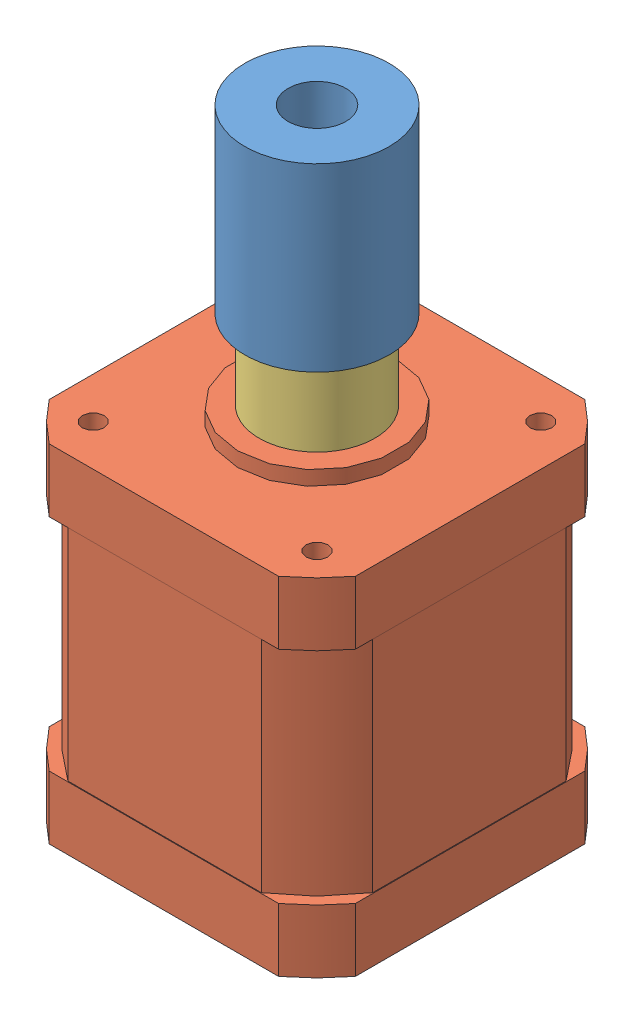
SolidWorks assembly z_motor_thrust_coupling_assembly, configuration Default. Lengths in mm.
Overall size (42.42 86 42.42).
4 component instances, 4 part files, 0 mates.
Components (placement in the parent):
- plumb_coupling_8mm_to_5mm-1: plumb_coupling_8mm_to_5mm [Default] at (304.071 41.773 434.2083) x (0.979819 0 -0.199886) z (0.199886 0 0.979819) size (20 25 20)
- 17HM19-2004S-1: 17HM19-2004S [Default] at (304.071 28.773 434.2083) x (0 0 -1) z (0 1 0) size (42.42 42.42 72)
- z_thrust_bearing_spacer_Z Thrust Bearing Spacer-1: z_thrust_bearing_spacer_Z Thrust Bearing Spacer [Default] at (304.071 30.773 434.2083) x (0.992689 0 -0.120701) z (0.120701 0 0.992689) size (16 10.8 16)
- m5_shim_0.2mm_thick_98089A246_98089A246-1: m5_shim_0.2mm_thick_98089A246_98089A246 [Default] at (304.071 41.573 434.2083) x (0.943035 0 -0.332694) z (0.332694 0 0.943035) size (10 0.2 10)
